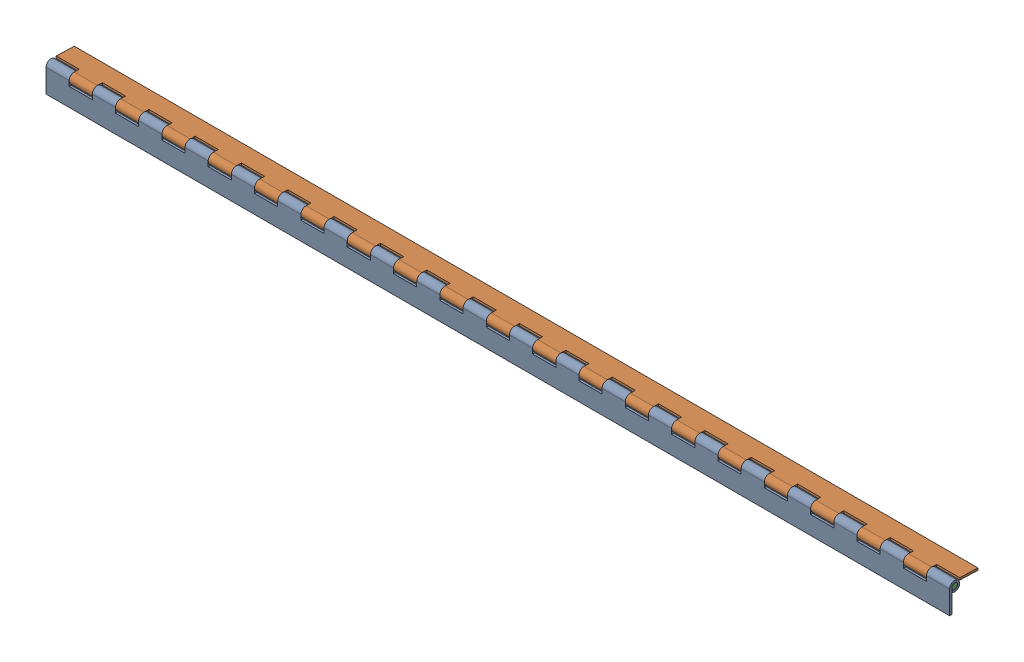
SolidWorks assembly FE-00014-02_ASM, configuration Default. Lengths in mm.
Overall size (990.6 31.05 31.22).
3 component instances, 3 part files, 0 mates.
Components (placement in the parent):
- 01_39_INCH-1: 01_39_INCH [Default] at origin size (990.6 30.86 10.92)
- 02_39_INCH-1: 02_39_INCH [Default] at (0 5.4577 -5.6516) x (-1 0 0) z (0 0.999391 -0.034899) size (990.6 30.86 10.92)
- 03_39_INCH-1: 03_39_INCH [Default] at (0 0 -5.461) size (990.6 6.35 6.35)
